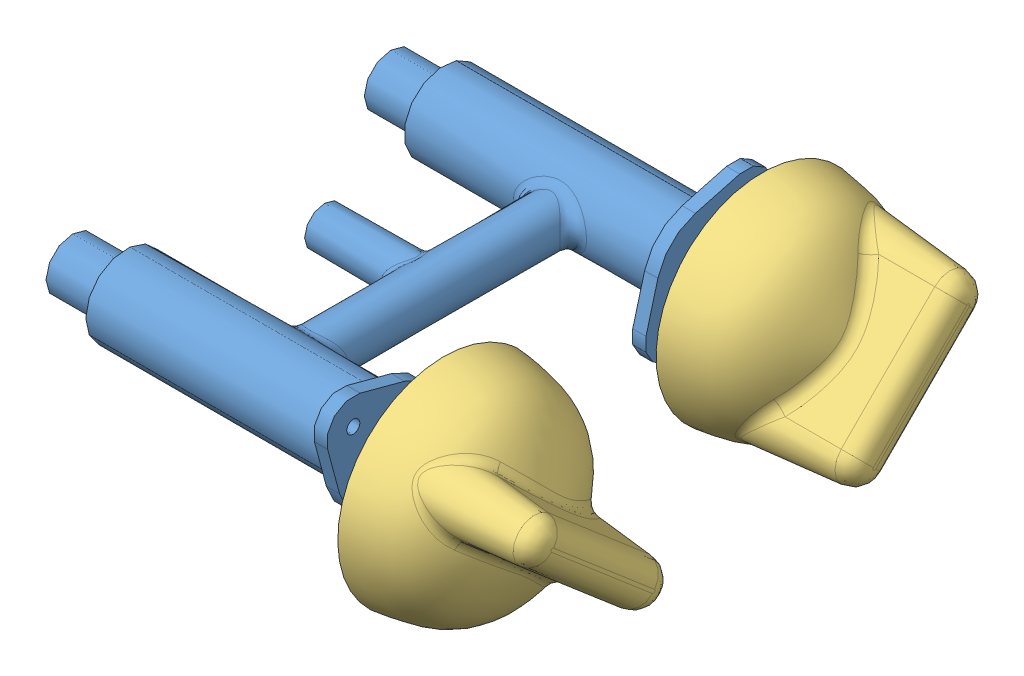
SolidWorks assembly Valve Assembly, configuration Default. Lengths in mm.
Overall size (127 125.52 202.58).
5 component instances, 3 part files, 13 mates.
Components (placement in the parent):
- Valve Mixer 1-10-1: Valve Mixer 1-10 [Default] at origin
- Control Shaft-3: Control Shaft [Default] at (3.175 0 38.1) x (1 0 0) z (0 -0.078346 0.996926)
- Control Shaft-4: Control Shaft [Default] at (3.175 0 -38.1) x (1 0 0) z (0 -0.999998 -0.002065)
- Lofted Control Knob-1: Lofted Control Knob [Default] at (41.275 0 38.1) x (0 0.649535 0.760332) z (0 0.760332 -0.649535)
- Lofted Control Knob-2: Lofted Control Knob [Default] at (41.275 0 -38.1) x (0 -0.708566 0.705645) z (0 0.705645 0.708566)
Mates (geometry in assembly coordinates):
- Coincident3: coincident aligned: plane of Valve Mixer 1-10-1 through (0 0 0) normal (0 0 1); plane of assembly through (0 0 0) normal (0 0 1)
- Coincident4: coincident aligned: plane of Valve Mixer 1-10-1 through (0 0 0) normal (0 1 0); plane of assembly through (0 0 0) normal (0 1 0)
- Coincident5: coincident aligned: plane of Valve Mixer 1-10-1 through (0 0 0) normal (1 0 0); plane of assembly through (0 0 0) normal (1 0 0)
- Concentric3: concentric anti-aligned: cylinder of Valve Mixer 1-10-1 through (3.175 0 38.1) axis (1 0 0) radius 6.35; cylinder of Control Shaft-3 through (60.325 0 38.1) axis (-1 0 0) radius 5.5563
- Concentric4: concentric anti-aligned: cylinder of Valve Mixer 1-10-1 through (3.175 0 -38.1) axis (1 0 0) radius 6.35; cylinder of Control Shaft-4 through (60.325 0 -38.1) axis (-1 0 0) radius 5.5563
- Coincident6: coincident anti-aligned: plane of Valve Mixer 1-10-1 through (3.175 0 38.1) normal (1 0 0); plane of Control Shaft-3 through (3.175 0 38.1) normal (-1 0 0)
- Coincident7: coincident anti-aligned: plane of Valve Mixer 1-10-1 through (3.175 0 -38.1) normal (1 0 0); plane of Control Shaft-4 through (3.175 0 -38.1) normal (-1 0 0)
- Concentric5: concentric aligned: cylinder of Control Shaft-3 through (60.325 0 38.1) axis (-1 0 0) radius 5.5563; cylinder of Lofted Control Knob-1 through (60.325 0 38.1) axis (-1 0 0) radius 5.588
- Parallel1: parallel anti-aligned: plane of Control Shaft-3 through (47.625 1.1655 43.5326) normal (0 0.996926 0.078346); plane of Lofted Control Knob-1 through (60.325 4.2487 34.4704) normal (0 -0.996926 -0.078346)
- Coincident8: coincident anti-aligned: plane of Control Shaft-3 through (60.325 0 38.1) normal (1 0 0); plane of Lofted Control Knob-1 through (60.325 0 38.1) normal (-1 0 0)
- Concentric6: concentric aligned: cylinder of Control Shaft-4 through (60.325 0 -38.1) axis (-1 0 0) radius 5.5563; cylinder of Lofted Control Knob-2 through (60.325 0 -38.1) axis (-1 0 0) radius 5.588
- Parallel2: parallel anti-aligned: plane of Control Shaft-4 through (47.625 -5.3279 -36.5235) normal (0 -0.002065 0.999998); plane of Lofted Control Knob-2 through (60.325 3.9431 -34.1405) normal (0 0.002065 -0.999998)
- Coincident9: coincident anti-aligned: plane of Control Shaft-4 through (60.325 0 -38.1) normal (1 0 0); plane of Lofted Control Knob-2 through (60.325 0 -38.1) normal (-1 0 0)
